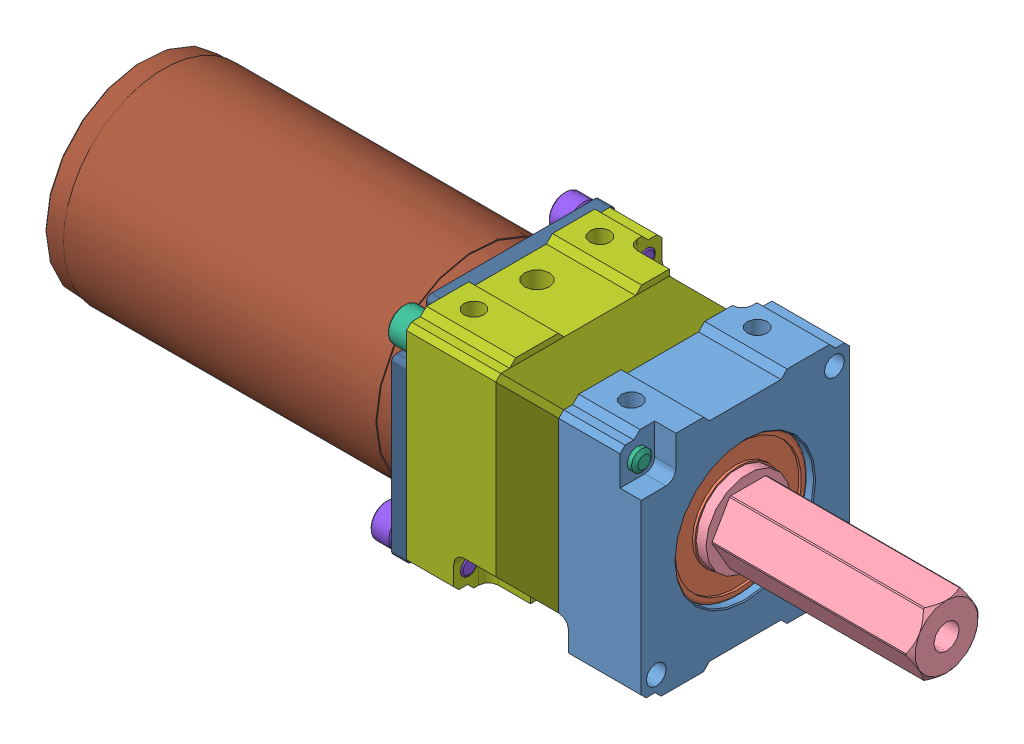
SolidWorks assembly VersaPlanetary_v2_Single_Stage_10_1_with_BAG, configuration Default. Lengths in mm.
Overall size (163.4 63.56 63.56).
29 component instances, 19 part files, 0 mates.
Components (placement in the parent):
- 217-2625-026 Rev1-1: 217-2625-026 Rev1 [Default] at (-6.5 22.225 0) x (0 -1 0) z (-1 0 0) size (44.45 42 18.13)
- 217-2742-001 Rev4-1: 217-2742-001 Rev4 [Default] at (0.2002 22.225 0) x (1 0 0) z (0 -0.092627 0.995701) size (7 28 28)
- 217-2742-001 Rev4-2: 217-2742-001 Rev4 [Default] at (8.2002 22.225 0) size (7 28 28)
- 217-2625-017 Rev1_9714K61-1: 217-2625-017 Rev1_9714K61 [Default] at (7.42 22.3002 -0.342) x (0 0.56703 0.823697) z (0 -0.823697 0.56703) size (28.51 4.98 30.18)
- 217-2625-003 Rev1-1: 217-2625-003 Rev1 [Default] at (7.4478 22.225 0) x (0 -1 0) z (1 0 0) size (17 17 64.12)
- 217-2625-018 Rev1_98541A410-1: 217-2625-018 Rev1_98541A410 [Default] at (-0.7046 22.225 0) x (1 0 0) z (0 -0.017452 0.999848) size (1 19.6 17.4)
- 832-1750-Ring-Gear-Screw_SSA0832-0500ZC-1: 832-1750-Ring-Gear-Screw_SSA0832-0500ZC [Default] at (-30.7 4.725 -17.5) x (0 0.997447 0.071411) z (0 -0.071411 0.997447) size (6.73 48.51 6.73)
- 832-1750-Ring-Gear-Screw_SSA0832-0500ZC-2: 832-1750-Ring-Gear-Screw_SSA0832-0500ZC [Default] at (-30.7 39.725 17.5) x (0 0.005929 0.999982) z (0 -0.999982 0.005929) size (6.73 48.51 6.73)
- 217-2625-025 Rev1-1: 217-2625-025 Rev1 [Default] at (-23.2 22.225 0) x (0 -1 0) z (-1 0 0) size (44.45 42 18)
- 217-4649-002 Rev1_SSA0832-0500ZC-1: 217-4649-002 Rev1_SSA0832-0500ZC [Default] at (-33.7 4.2645 17.9605) x (0 0.33842 -0.940995) z (0 0.940995 0.33842) size (6.73 16.76 6.73)
- 217-4649-002 Rev1_SSA0832-0500ZC-2: 217-4649-002 Rev1_SSA0832-0500ZC [Default] at (-33.7 40.1855 -17.9605) x (0 -0.308932 -0.951084) z (0 0.951084 -0.308932) size (6.73 16.76 6.73)
- 217-4649-006 Rev1_SSA0004-008BA-1: 217-4649-006 Rev1_SSA0004-008BA [Default] at (-30.7 22.225 12.5) x (0 0.5 -0.866025) z (0 -0.866025 -0.5) size (7 14 7)
- 217-4649-006 Rev1_SSA0004-008BA-2: 217-4649-006 Rev1_SSA0004-008BA [Default] at (-30.7 22.225 -12.5) x (0 -0.5 0.866025) z (0 0.866025 0.5) size (7 14 7)
- 217-2822-003 Rev4-1: 217-2822-003 Rev4 [Default] at (-32.2 22.225 0) x (0 -1 0) z (-1 0 0) size (42 42 4.8)
- 217-3351 Rev2-1: 217-3351 Rev2 [Default] at (-33.7 22.225 0) x (0 0 1) z (1 0 0) size (59.11 59.11 84.5)
- 217-2820 Rev1_Public-1: 217-2820 Rev1_Public [Default] at (-4.6546 22.225 0) x (0 -0.456494 0.889726) z (-1 0 0) size (39.26 38.9 17.4)
  - 217-2625-100-1: 217-2625-100 [Default] at origin size (39.26 38.9 12.7)
    - 217-2625-008 Rev1-1: 217-2625-008 Rev1 [Default] at origin size (34.7 34.7 4.7)
    - 217-2625-010 Rev1-1: 217-2625-010 Rev1 [Default] at (0 10.193 3.65) x (0.999813 0.019336 0) z (0 0 1) size (4 4 12)
    - 217-2625-010 Rev1-2: 217-2625-010 Rev1 [Default] at (8.691 -5.3258 3.65) size (4 4 12)
    - 217-2625-010 Rev1-3: 217-2625-010 Rev1 [Default] at (-8.691 -5.3258 3.65) size (4 4 12)
    - 217-2625-005 Rev1_Planet_Revolving_Follower01-1: 217-2625-005 Rev1_Planet_Revolving_Follower01 [Default] at (8.691 -5.3258 6.35) x (0.932816 0.360354 0) z (0 0 1) size (16.91 16.92 8)
    - 217-2625-005 Rev1_Planet_Revolving_Follower01-2: 217-2625-005 Rev1_Planet_Revolving_Follower01 [Default] at (-8.691 -5.3258 6.35) x (-0.932788 -0.360426 0) z (0 0 1) size (16.91 16.92 8)
    - 217-2625-005 Rev1_Planet_Revolving_Follower01-3: 217-2625-005 Rev1_Planet_Revolving_Follower01 [Default] at (0 10.193 6.35) x (0.893583 0.448898 0) z (0 0 1) size (16.91 16.92 8)
  - 217-2625-007 Rev1_Public-1: 217-2625-007 Rev1_Public [Default] at (0 0 6.7) x (0.992772 0.120019 0) z (0 0 1) size (14.49 14.49 12.72)
- 217-2816-001 Rev1-1: 217-2816-001 Rev1 [Default] at (-6.35 22.225 0) x (0 -1 0) z (1 0 0) size (42 42 14.5)
- 217-4649-001 Rev1-1: 217-4649-001 Rev1 [Default] at (-20.046 22.225 0) x (0 -1 0) z (1 0 0) size (18 18 13)
- 217-4649-007 Rev1_94105A824-1: 217-4649-007 Rev1_94105A824 [Default] at (-25.521 22.225 -6.7835) x (-0.996104 -0.088191 0) z (0 0 -1) size (4.83 4.83 4.9)
- 217-2625-011 Rev1-1: 217-2625-011 Rev1 [Default] at (-24.7818 22.225 0) x (0 0 1) z (0 -1 0) size (8.01 7.5 7.94)
